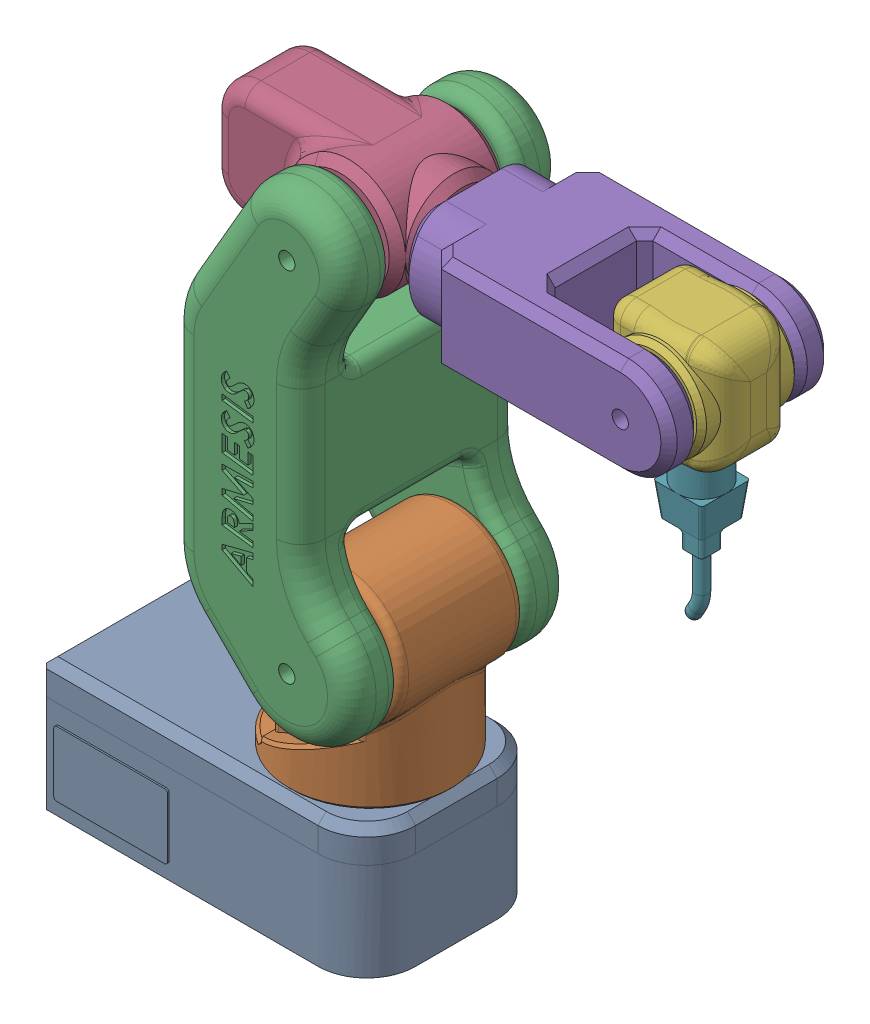
SolidWorks assembly Robot Assembly, configuration Default. Lengths in mm.
Overall size (388.66 417 136).
8 component instances, 8 part files, 20 mates.
Components (placement in the parent):
- Base-1: Base [Default] at (643.0925 868.898 1278.0313) size (200.01 80 111.01)
- First Member-1: First Member [Default] at (715.8382 890.898 1281.5372) size (106.65 120 100)
- Second Member-1: Second Member [Default] at (732.4925 970.898 1281.5372) size (112.01 295 136)
- Third Member-1: Third Member [Default] at (732.4925 1190.898 1281.5372) size (128.74 70 70)
- Fourth Member-1: Fourth Member [Default] at (784.4925 1190.898 1281.5372) size (175 60 100)
- Fifth Member-1: Fifth Member [Default] at (919.4925 1190.898 1281.5372) size (70 70 60)
- Sixth Member-1: Sixth Member [Default] at (919.4925 1153.898 1281.5372) size (30 89.67 30) (hidden)
- End Effector-1: End Effector [Default] at (919.4925 1155.898 1281.5372) x (0.99864 0 0.052137) z (-0.052137 0 0.99864) size (30 5 30)
Mates (geometry in assembly coordinates):
- Concentric1: concentric anti-aligned: cylinder of Base-1 through (715.8382 864.898 1281.5372) axis (0 1 0) radius 5; cylinder of First Member-1 through (715.8382 970.898 1281.5372) axis (0 -1 0) radius 5
- Distance2: distance = 2 mm anti-aligned: plane of Base-1 through (643.0925 888.898 1278.0313) normal (0 1 0); plane of First Member-1 through (715.8382 890.898 1281.5372) normal (0 -1 0)
- Concentric2: concentric anti-aligned: cylinder of First Member-1 through (732.4925 970.898 1231.5372) axis (0 0 1) radius 5; cylinder of Second Member-1 through (732.4925 970.898 1349.5372) axis (0 0 -1) radius 5
- Coincident3: coincident anti-aligned: plane of First Member-1 through (679.2964 994.6285 1319.5372) normal (0 0 1); plane of Second Member-1 through (732.4925 970.898 1319.5372) normal (0 0 -1)
- Concentric3: concentric anti-aligned: cylinder of Second Member-1 through (732.4925 1190.898 1349.5372) axis (0 0 -1) radius 5; cylinder of Third Member-1 through (732.4925 1190.898 1246.5347) axis (0 0 1) radius 5
- Width1: width anti-aligned: plane of Third Member-1 through (732.4925 1190.898 1316.5372) normal (0 0 1); plane of Second Member-1 through (732.4925 1190.898 1246.5372) normal (0 0 -1); plane of Third Member-1 through (732.4925 970.898 1319.5372) normal (0 0 -1); plane of Second Member-1 through (732.4925 970.898 1243.5372) normal (0 0 1)
- Concentric4: concentric aligned: cylinder of Third Member-1 through (732.4925 1190.898 1281.5372) axis (1 0 0) radius 5; cylinder of Fourth Member-1 through (774.4925 1190.898 1281.5372) axis (1 0 0) radius 5
- Distance1: distance = 2 mm anti-aligned: plane of Fourth Member-1 through (774.4925 1190.898 1281.5372) normal (-1 0 0); plane of Third Member-1 through (772.4925 1190.898 1281.5372) normal (1 0 0)
- Concentric5: concentric aligned: cylinder of Fourth Member-1 through (919.4925 1190.898 1231.5372) axis (0 0 1) radius 5; cylinder of Fifth Member-1 through (919.4925 1190.898 1251.5372) axis (0 0 1) radius 5
- Width2: width anti-aligned: plane of Fifth Member-1 through (919.4925 1190.898 1311.5372) normal (0 0 1); plane of Fourth Member-1 through (919.4925 1190.898 1251.5372) normal (0 0 -1); plane of Fifth Member-1 through (784.4925 1004.693 1311.5372) normal (0 0 -1); plane of Fourth Member-1 through (784.4925 1004.693 1251.5372) normal (0 0 1)
- Concentric6: concentric aligned: cylinder of Fifth Member-1 through (919.4925 1155.898 1281.5372) axis (0 1 0) radius 5; cylinder of Sixth Member-1 through (919.4925 1133.898 1281.5372) axis (0 1 0) radius 5
- Distance3: distance = 2 mm anti-aligned: plane of Sixth Member-1 through (919.4925 1153.898 1281.5372) normal (0 1 0); plane of Fifth Member-1 through (919.4925 1155.898 1281.5372) normal (0 -1 0)
- Parallel1: parallel aligned: plane of Base-1 through (565.8382 888.898 1223.6671) normal (-1 0 0); plane of First Member-1 through (692.4925 970.898 1231.5372) normal (-1 0 0)
- Parallel2: parallel aligned: plane of Base-1 through (565.8382 888.898 1333.6671) normal (0 0 1); plane of Fourth Member-1 through (784.4925 1004.693 1331.5372) normal (0 0 1)
- Parallel3: parallel aligned: plane of Base-1 through (565.8382 888.898 1223.6671) normal (-1 0 0); plane of Second Member-1 through (660.4829 970.898 1349.5372) normal (-1 0 0)
- Parallel4: parallel aligned: plane of Base-1 through (565.8382 888.898 1223.6671) normal (-1 0 0); plane of Third Member-1 through (643.7489 1190.898 1306.5372) normal (-1 0 0)
- Parallel5: parallel aligned: plane of Base-1 through (565.8382 888.898 1223.6671) normal (-1 0 0); plane of Fifth Member-1 through (884.4925 1225.898 1306.5372) normal (-1 0 0)
- Parallel8: parallel aligned: plane of Fifth Member-1 through (954.4925 1225.898 1306.5372) normal (1 0 0); plane of Sixth Member-1 through (932.3904 1103.898 1281.5372) normal (1 0 0)
- Concentric7: concentric aligned: cylinder of Fifth Member-1 through (919.4925 1155.898 1281.5372) axis (0 1 0) radius 5; cylinder of End Effector-1 through (919.4925 1150.898 1281.5372) axis (0 1 0) radius 5
- Coincident14: coincident anti-aligned: plane of Fifth Member-1 through (919.4925 1155.898 1281.5372) normal (0 -1 0); plane of End Effector-1 through (919.4925 1155.898 1281.5372) normal (0 1 0)
